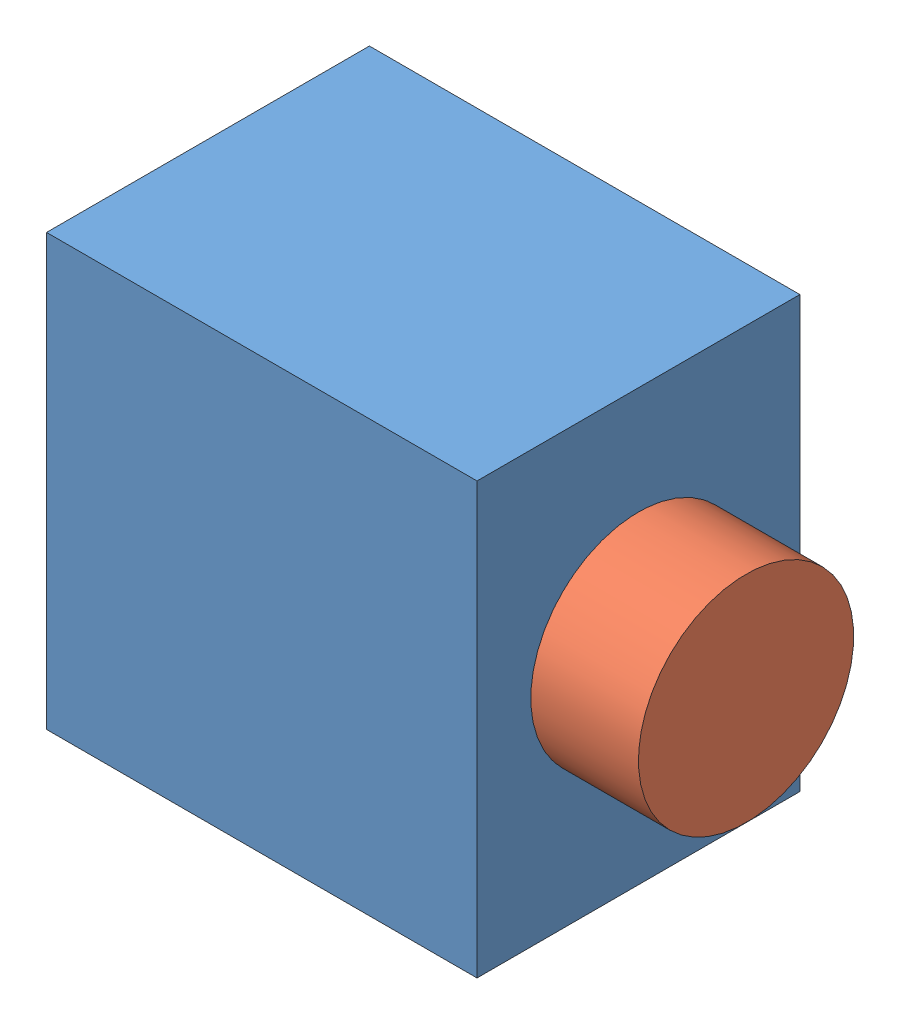
SolidWorks assembly servo, configuration Default. Lengths in mm.
Overall size (25 20 15).
2 component instances, 2 part files, 1 mates.
Components (placement in the parent):
- Part5-2: Part5 [Default] at origin size (20 20 15)
- Part6-2: Part6 [Default] at (0 10 0) x (0 0.60442 0.796666) z (0 0.796666 -0.60442) size (10 15 10)
Mates (geometry in assembly coordinates):
- Coincident3: coincident aligned: circle of Part5-2; circle of Part6-2
